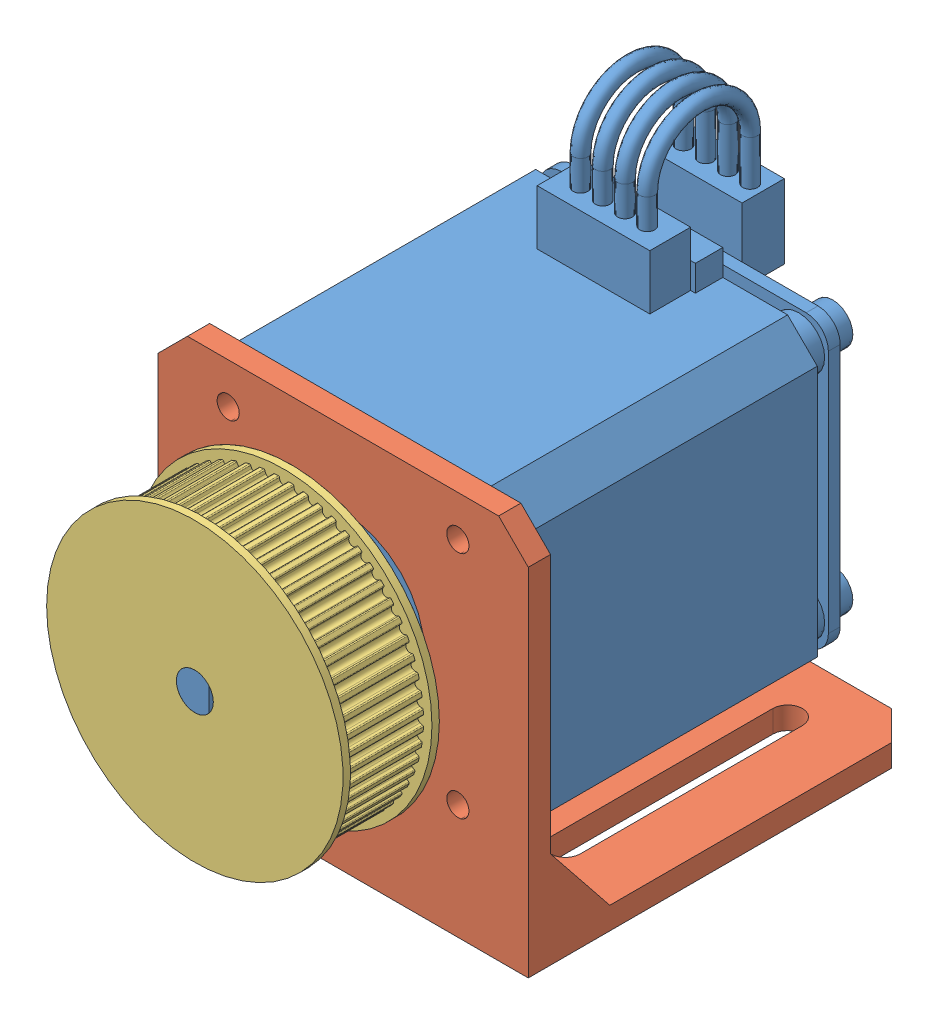
SolidWorks assembly stepper_subassy_60t, configuration Default. Lengths in mm.
Overall size (50 71.4 73.3).
3 component instances, 3 part files, 6 mates.
Components (placement in the parent):
- smart stepper-1: smart stepper [Default] at origin size (45 61.4 73.3)
- stepper bracket-1: stepper bracket [Default] at (0 -5 3) x (-1 0 0) z (0 0 -1) size (50 52 53)
- pulley 60t-1: pulley 60t [Default] at (19.0986 -19.0986 22) x (0 0 -1) z (1 0 0) size (18 42.3 42.3)
Mates (geometry in assembly coordinates):
- Concentric1: concentric anti-aligned: cylinder of smart stepper-1 through (0 0 2) axis (0 0 -1) radius 11; cylinder of stepper bracket-1 through (0 0 0) axis (0 0 1) radius 11
- Concentric2: concentric anti-aligned: cylinder of smart stepper-1 through (-15.5 15.5 23) axis (0 0 -1) radius 1.5; cylinder of stepper bracket-1 through (-15.5 15.5 0) axis (0 0 1) radius 1.5
- Coincident1: coincident anti-aligned: plane of smart stepper-1 through (0 0 0) normal (0 0 1); plane of stepper bracket-1 through (0 -5 0) normal (0 0 -1)
- Concentric3: concentric anti-aligned: cylinder of smart stepper-1 through (0 0 -5.0502) axis (0 0 1) radius 2.5; cylinder of pulley 60t-1 through (0 0 36.1421) axis (0 0 -1) radius 2.5
- Coincident2: coincident aligned: plane of smart stepper-1 through (0 0 23) normal (0 0 1); plane of pulley 60t-1 through (0 0 23) normal (0 0 1)
- Parallel1: parallel aligned: plane of pulley 60t-1 through (19.0986 -19.0986 22) normal (1 0 0)
